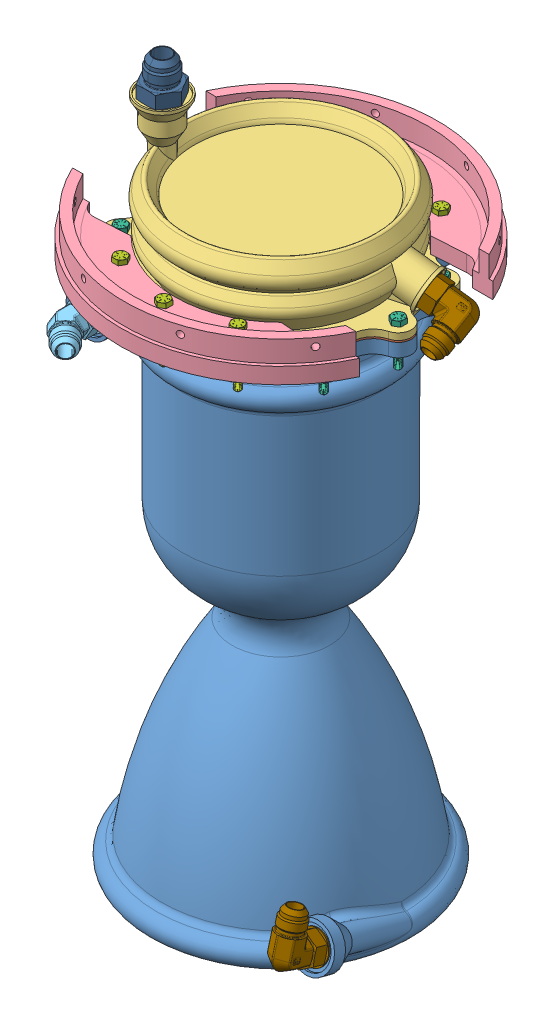
SolidWorks assembly 10013-R01_Engine, configuration Default. Lengths in mm.
Overall size (304.92 639.04 304.8).
21 component instances, 10 part files, 30 mates.
Components (placement in the parent):
- 13100_R02_Thrust_Chamber-2: 13100_R02_Thrust_Chamber [Default] at origin size (262.96 497.78 253.25)
- Gasket-2: Gasket [Default] at (0 280.7399 0) size (248.92 1.59 248.92)
- 13008-R01_Injector_Plate-2: 13008-R01_Injector_Plate [Default] at (150.3244 162.3751 158.3501) x (-0.965926 0 0.258819) z (-0.258819 0 -0.965926) size (243.88 107.11 241.3)
- 13007-R01_Thrust_Mount-3: 13007-R01_Thrust_Mount [Default] at (0 288.6774 0) x (0 0 -1) z (1 0 0) size (304.8 35.64 277.08)
- 10_V5OX-S-2: 10_V5OX-S [Default] at (-93.6214 237.7504 111.76) size (44.94 39.22 63.51)
- 90201A117_EXTREME-STRENGTH GRADE 9 STEEL CAP SCREW-13: 90201A117_EXTREME-STRENGTH GRADE 9 STEEL CAP SCREW [90201A117] at (96.787 272.0087 55.88) x (0 -1 0) z (0 0 1) size (43.33 12.83 11.11)
- 91257A550_HIGH-STRENGTH GRADE 8 STEEL CAP SCREW-7: 91257A550_HIGH-STRENGTH GRADE 8 STEEL CAP SCREW [91257A550] at (55.88 280.7002 96.787) x (0 -1 0) z (0 0 1) size (55.63 12.83 11.11)
- 94895A029_ZINC YELLOW-CHROMATE PLATED STEEL HEX NUT-33: 94895A029_ZINC YELLOW-CHROMATE PLATED STEEL HEX NUT [94895A029] at (96.787 265.2618 55.88) x (-1 0 0) z (0 1 0) size (11.11 12.83 7.14)
- 10_C5OX-S-1: 10_C5OX-S [Default] at (112.0104 282.4233 -26.0534) x (0.05538 -0.433018 0.899683) z (0.447836 0.816118 0.365232) size (55.44 55.55 38.35)
- 10_C5OX-S-2: 10_C5OX-S [Default] at (102.5614 -170.5898 88.4045) x (0 0.965926 -0.258819) z (1 0 0) size (55.44 55.55 38.35)
- 12_F5OX-S-1: 12_F5OX-S [Default] at (-89.1216 396.9815 23.8801) x (0 1 0) z (0 0 1) size (50.04 36.67 31.75)
- 91257A550_HIGH-STRENGTH GRADE 8 STEEL CAP SCREW-8: 91257A550_HIGH-STRENGTH GRADE 8 STEEL CAP SCREW [91257A550] at (0 280.7002 111.76) x (0 -1 0) z (-0.5 0 0.866025) size (55.63 12.83 11.11)
- 91257A550_HIGH-STRENGTH GRADE 8 STEEL CAP SCREW-9: 91257A550_HIGH-STRENGTH GRADE 8 STEEL CAP SCREW [91257A550] at (-55.88 280.7002 96.787) x (0 -1 0) z (-0.866025 0 0.5) size (55.63 12.83 11.11)
- 91257A550_HIGH-STRENGTH GRADE 8 STEEL CAP SCREW-10: 91257A550_HIGH-STRENGTH GRADE 8 STEEL CAP SCREW [91257A550] at (-55.88 280.7002 -96.787) x (0 -1 0) z (0 0 -1) size (55.63 12.83 11.11)
- 91257A550_HIGH-STRENGTH GRADE 8 STEEL CAP SCREW-11: 91257A550_HIGH-STRENGTH GRADE 8 STEEL CAP SCREW [91257A550] at (0 280.7002 -111.76) x (0 -1 0) z (0.5 0 -0.866025) size (55.63 12.83 11.11)
- 91257A550_HIGH-STRENGTH GRADE 8 STEEL CAP SCREW-12: 91257A550_HIGH-STRENGTH GRADE 8 STEEL CAP SCREW [91257A550] at (55.88 280.7002 -96.787) x (0 -1 0) z (0.866025 0 -0.5) size (55.63 12.83 11.11)
- 90201A117_EXTREME-STRENGTH GRADE 9 STEEL CAP SCREW-14: 90201A117_EXTREME-STRENGTH GRADE 9 STEEL CAP SCREW [90201A117] at (111.7604 272.0087 0.0006) x (0 -1 0) z (0.5 0 0.866025) size (43.33 12.83 11.11)
- 90201A117_EXTREME-STRENGTH GRADE 9 STEEL CAP SCREW-15: 90201A117_EXTREME-STRENGTH GRADE 9 STEEL CAP SCREW [90201A117] at (96.788 272.0087 -55.879) x (0 -1 0) z (0.866025 0 0.5) size (43.33 12.83 11.11)
- 90201A117_EXTREME-STRENGTH GRADE 9 STEEL CAP SCREW-16: 90201A117_EXTREME-STRENGTH GRADE 9 STEEL CAP SCREW [90201A117] at (-96.7844 272.0087 -55.8807) x (0 -1 0) z (0 0 -1) size (43.33 12.83 11.11)
- 90201A117_EXTREME-STRENGTH GRADE 9 STEEL CAP SCREW-17: 90201A117_EXTREME-STRENGTH GRADE 9 STEEL CAP SCREW [90201A117] at (-111.7577 272.0087 -0.0013) x (0 -1 0) z (-0.5 0 -0.866025) size (43.33 12.83 11.11)
- 90201A117_EXTREME-STRENGTH GRADE 9 STEEL CAP SCREW-18: 90201A117_EXTREME-STRENGTH GRADE 9 STEEL CAP SCREW [90201A117] at (-96.7853 272.0087 55.8783) x (0 -1 0) z (-0.866025 0 -0.5) size (43.33 12.83 11.11)
Mates (geometry in assembly coordinates):
- Coincident1: coincident: plane of Gasket-2 through (0 280.7399 0) normal (0 0 1); plane of assembly through (0 0 0) normal (0 0 1)
- Coincident2: coincident: plane of Gasket-2 through (0 280.7399 0) normal (1 0 0); plane of assembly through (0 0 0) normal (1 0 0)
- Coincident3: coincident: plane of 13100_R02_Thrust_Chamber-2 through (87.2714 280.7399 0) normal (0 1 0); plane of Gasket-2 through (0 280.7399 0) normal (0 -1 0)
- Coincident4: coincident: plane of Gasket-2 through (0 282.3274 0) normal (0 1 0); plane of 13008-R01_Injector_Plate-2 through (0 282.3274 0) normal (0 -1 0)
- Concentric1: concentric: cylinder of 13100_R02_Thrust_Chamber-2 through (111.76 -217.044 0) axis (0 1 0) radius 3.302; cylinder of 13008-R01_Injector_Plate-2 through (111.76 298.0169 0) axis (0 -1 0) radius 3.302
- Concentric3: concentric: cylinder of 13100_R02_Thrust_Chamber-2 through (96.787 -217.044 -55.88) axis (0 1 0) radius 3.302; cylinder of 13008-R01_Injector_Plate-2 through (96.787 298.0169 -55.88) axis (0 -1 0) radius 3.302
- Concentric4: concentric: cylinder of 13100_R02_Thrust_Chamber-2 through (115.3836 -205.8035 0) axis (0 -0.258819 -0.965926) radius 9.7828; cylinder of 10_C5OX-S-2 through (115.3836 -184.0205 81.2951) axis (0 -0.258819 -0.965926) radius 11.0268
- Coincident5: coincident: plane of 13100_R02_Thrust_Chamber-2 through (115.3836 -171.5644 80.4951) normal (0 0.258819 0.965926); plane of 10_C5OX-S-2 through (115.3836 -183.3861 83.6627) normal (0 -0.258819 -0.965926)
- Parallel1: parallel: plane of 10_C5OX-S-2 through (102.5614 -170.5898 88.4045) normal (1 0 0); plane of assembly through (0 0 0) normal (1 0 0)
- Concentric5: concentric: cylinder of 13008-R01_Injector_Plate-2 through (-89.1216 282.3264 23.8801) axis (0 1 0) radius 9.525; cylinder of 12_F5OX-S-1 through (-89.1216 387.8045 23.8801) axis (0 -1 0) radius 13.3998
- Coincident7: coincident: plane of 13008-R01_Injector_Plate-2 through (-89.1216 387.0501 23.8801) normal (0 1 0); plane of 12_F5OX-S-1 through (-89.1216 387.0501 23.8801) normal (0 -1 0)
- Parallel2: parallel: plane of 12_F5OX-S-1 through (-89.1216 396.9815 23.8801) normal (0 0 1); plane of assembly through (0 0 0) normal (0 0 1)
- Concentric6: concentric: cylinder of 13100_R02_Thrust_Chamber-2 through (-93.6214 237.7504 0) axis (0 0 -1) radius 9.7828; cylinder of 10_V5OX-S-2 through (-93.6214 237.7504 85.581) axis (0 0 -1) radius 11.0268
- Coincident9: coincident: plane of 13100_R02_Thrust_Chamber-2 through (-93.6214 249.9892 87.884) normal (0 0 1); plane of 10_V5OX-S-2 through (-93.6214 237.7504 87.884) normal (0 0 -1)
- Parallel3: parallel: plane of 10_V5OX-S-2 through (-93.6214 237.7504 111.76) normal (0 1 0); plane of assembly through (0 0 0) normal (0 1 0)
- Concentric7: concentric: cylinder of 13008-R01_Injector_Plate-2 through (-113.6468 396.6741 30.4516) axis (0.892399 -0.382683 -0.239118) radius 7.9375; cylinder of 10_C5OX-S-1 through (107.9057 301.6668 -28.9133) axis (-0.892399 0.382683 0.239118) radius 11.0268
- Coincident11: coincident: plane of 13008-R01_Injector_Plate-2 through (110.0931 300.7288 -29.4994) normal (0.892399 -0.382683 -0.239118); plane of 10_C5OX-S-1 through (110.0931 300.7288 -29.4994) normal (-0.892399 0.382683 0.239118)
- Coincident13: coincident: plane of 13008-R01_Injector_Plate-2 through (0 288.6774 0) normal (0 1 0); plane of 13007-R01_Thrust_Mount-3 through (0 288.6774 0) normal (0 -1 0)
- Concentric9: concentric: cylinder of 13008-R01_Injector_Plate-2 through (55.88 298.0169 96.787) axis (0 -1 0) radius 3.302; cylinder of 13007-R01_Thrust_Mount-3 through (55.88 288.6774 96.787) axis (0 1 0) radius 3.302
- Concentric10: concentric: cylinder of 13008-R01_Injector_Plate-2 through (55.88 298.0169 -96.787) axis (0 -1 0) radius 3.302; cylinder of 13007-R01_Thrust_Mount-3 through (55.88 288.6774 -96.787) axis (0 1 0) radius 3.302
- Coincident14: coincident: plane of 13007-R01_Thrust_Mount-3 through (0 303.9174 0) normal (0 1 0); plane of 91257A550_HIGH-STRENGTH GRADE 8 STEEL CAP SCREW-7 through (59.0879 303.9174 102.3432) normal (0 -1 0)
- Concentric11: concentric: cylinder of 13007-R01_Thrust_Mount-3 through (55.88 288.6774 96.787) axis (0 1 0) radius 3.302; cylinder of 91257A550_HIGH-STRENGTH GRADE 8 STEEL CAP SCREW-7 through (55.88 303.9174 96.787) axis (0 -1 0) radius 3.175
- Coincident15: coincident: plane of 13008-R01_Injector_Plate-2 through (0 288.6774 0) normal (0 1 0); plane of 90201A117_EXTREME-STRENGTH GRADE 9 STEEL CAP SCREW-13 through (99.9949 288.6774 61.4363) normal (0 -1 0)
- Concentric12: concentric: cylinder of 13100_R02_Thrust_Chamber-2 through (96.787 -217.044 55.88) axis (0 1 0) radius 3.302; cylinder of 90201A117_EXTREME-STRENGTH GRADE 9 STEEL CAP SCREW-13 through (96.787 288.6774 55.88) axis (0 -1 0) radius 3.175
- Coincident16: coincident: plane of 13100_R02_Thrust_Chamber-2 through (0 268.0399 0) normal (0 -1 0); plane of 94895A029_ZINC YELLOW-CHROMATE PLATED STEEL HEX NUT-33 through (102.3432 268.0399 59.0879) normal (0 1 0)
- Concentric13: concentric: circle of 90201A117_EXTREME-STRENGTH GRADE 9 STEEL CAP SCREW-13; circle of 94895A029_ZINC YELLOW-CHROMATE PLATED STEEL HEX NUT-33
- Parallel6: parallel: plane of 91257A550_HIGH-STRENGTH GRADE 8 STEEL CAP SCREW-7 through (55.88 280.7002 96.787) normal (0 0 1); plane of assembly through (0 0 0) normal (0 0 1)
- Parallel7: parallel: plane of 90201A117_EXTREME-STRENGTH GRADE 9 STEEL CAP SCREW-13 through (96.787 272.0087 55.88) normal (0 0 1); plane of assembly through (0 0 0) normal (0 0 1)
- Parallel8: parallel: plane of 94895A029_ZINC YELLOW-CHROMATE PLATED STEEL HEX NUT-33 through (96.787 265.2618 55.88) normal (-1 0 0); plane of assembly through (0 0 0) normal (1 0 0)
- Perpendicular1: perpendicular: plane of 10_C5OX-S-1 through (110.6498 307.017 -42.7965) normal (-0.258819 0 -0.965926); plane of assembly through (0 0 0) normal (0 1 0)
